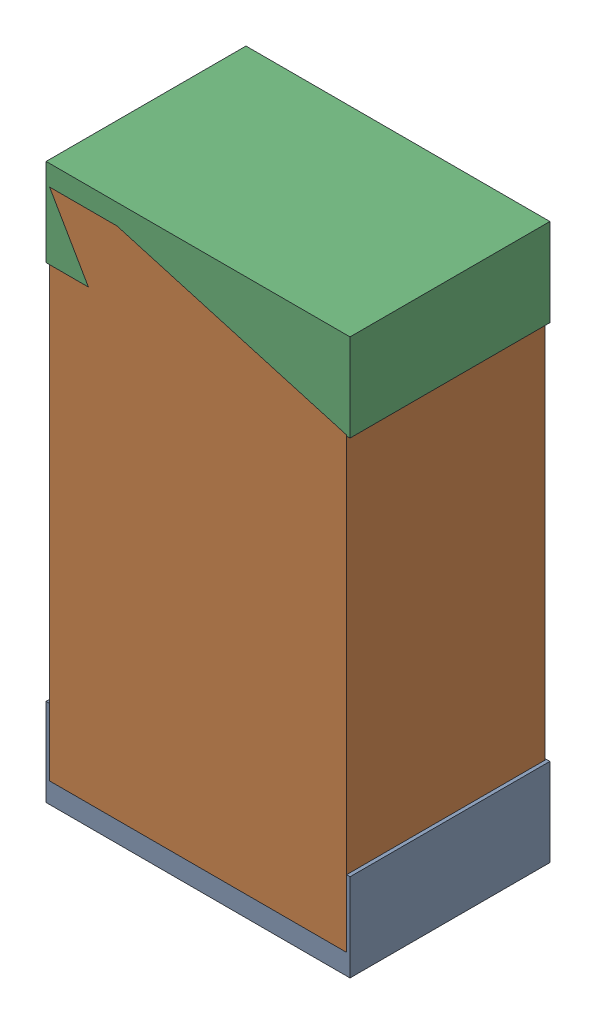
SolidWorks assembly R12, configuration Default. Lengths in mm.
Overall size (1.3 2.38 0.85).
6 component instances, 2 part files, 0 mates.
Components (placement in the parent):
- 402662288-1: 402662288 [Default] at (129.54 4.715 -1.9574) size (1.3 0.38 0.85)
  - Extruded_16-1: Extruded_16 [Default] at origin size (1.3 0.38 0.85)
- 402662416-1: 402662416 [Default] at (129.54 5.715 -1.9524) size (1.27 2.2 0.85)
  - Extruded_17-1: Extruded_17 [Default] at origin size (1.27 2.2 0.85)
- 402662288-2: 402662288 [Default] at (129.54 6.715 -1.9574) size (1.3 0.38 0.85)
  - Extruded_16-1: Extruded_16 [Default] at origin size (1.3 0.38 0.85)
